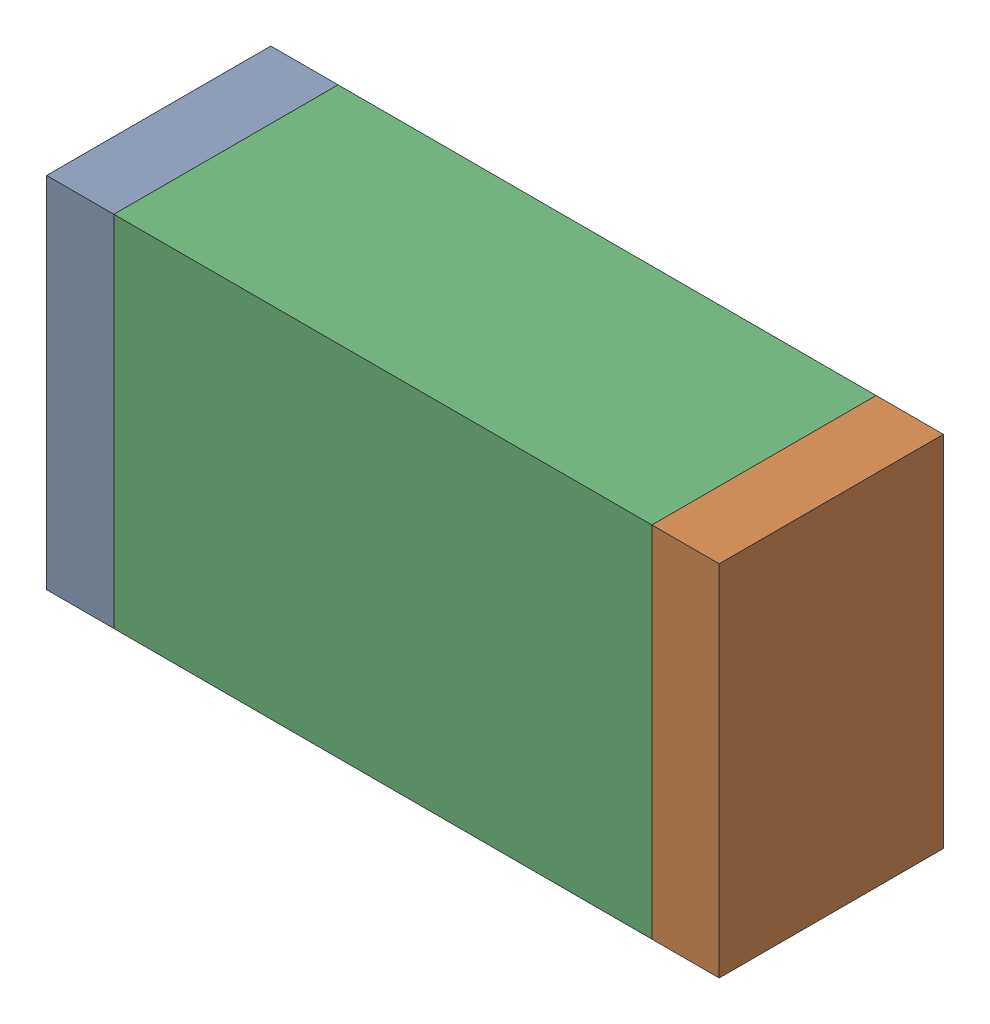
SolidWorks assembly R80, configuration Default. Lengths in mm.
Overall size (1.5 0.8 0.5).
6 component instances, 2 part files, 0 mates.
Components (placement in the parent):
- 836752496-1: 836752496 [Default] at (130.125 31.3 0) size (0.15 0.8 0.5)
  - Extruded_2-1: Extruded_2 [Default] at origin size (0.15 0.8 0.5)
- 836752496-2: 836752496 [Default] at (131.475 31.3 0) size (0.15 0.8 0.5)
  - Extruded_2-1: Extruded_2 [Default] at origin size (0.15 0.8 0.5)
- 836752368-1: 836752368 [Default] at (130.8 31.3 0) size (1.2 0.8 0.5)
  - Extruded-1: Extruded [Default] at origin size (1.2 0.8 0.5)
